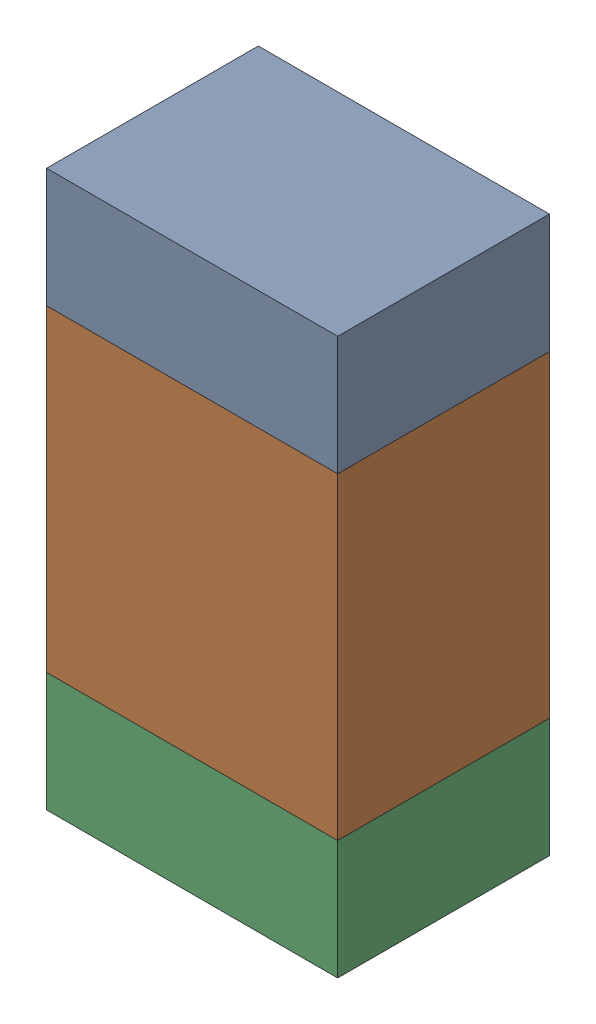
SolidWorks assembly R100_2PCB, configuration Default. Lengths in mm.
Overall size (0.55 1.05 0.4).
6 component instances, 2 part files, 0 mates.
Components (placement in the parent):
- 846483288-1: 846483288 [Default] at (117.1001 99.8124 0) size (0.55 0.22 0.4)
  - Extruded_12-1: Extruded_12 [Default] at origin size (0.55 0.22 0.4)
- 846483424-1: 846483424 [Default] at (117.1001 99.3999 0) size (0.55 0.6 0.4)
  - Extruded_13-1: Extruded_13 [Default] at origin size (0.55 0.6 0.4)
- 846483288-2: 846483288 [Default] at (117.1001 98.9874 0) size (0.55 0.22 0.4)
  - Extruded_12-1: Extruded_12 [Default] at origin size (0.55 0.22 0.4)
